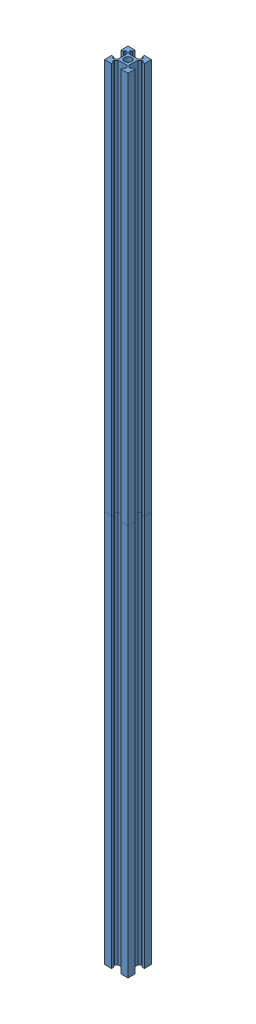
SolidWorks assembly Assem1, configuration Default. Lengths in mm.
Overall size (60 2000 60).
2 component instances, 1 part files, 4 mates.
Components (placement in the parent):
- AluminiumBar1M-1: AluminiumBar1M [Default] at (-159.6473 -25.0305 1080.6536) size (60 1000 60)
- AluminiumBar1M-2: AluminiumBar1M [Default] at (-159.6473 974.9695 1080.6536) x (0 0 -1) z (1 0 0) size (60 1000 60)
Mates (geometry in assembly coordinates):
- Concentric1: concentric aligned: cylinder of AluminiumBar1M-1 through (-159.6473 974.9695 1080.6536) axis (0 -1 0) radius 9; cylinder of AluminiumBar1M-2 through (-159.6473 1974.9695 1080.6536) axis (0 -1 0) radius 9
- Coincident1: coincident aligned: plane of AluminiumBar1M-1 through (-129.6473 974.9695 1092.6536) normal (1 0 0); plane of AluminiumBar1M-2 through (-129.6473 1974.9695 1110.6536) normal (1 0 0)
- Coincident2: coincident anti-aligned: plane of AluminiumBar1M-1 through (-159.6473 974.9695 1080.6536) normal (0 1 0); plane of AluminiumBar1M-2 through (-159.6473 974.9695 1080.6536) normal (0 -1 0)
- Concentric3: concentric aligned: cylinder of AluminiumBar1.1M-1 through (-755.3162 1175.7812 1919.7073) axis (1 0 0) radius 9; cylinder of AluminiumBar1.1M-2 through (-827.1869 1175.7812 1919.7073) axis (1 0 0) radius 9
